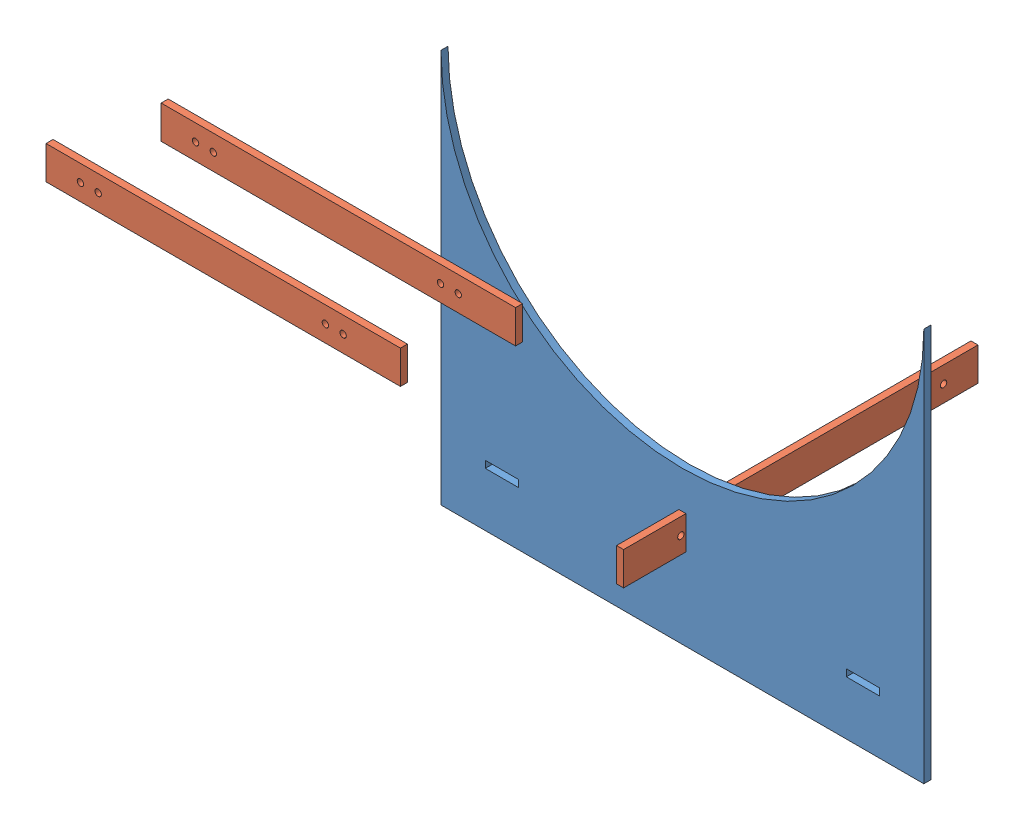
SolidWorks assembly Assem2, configuration Default. Lengths in mm.
Overall size (361.3 177.8 166.84).
4 component instances, 2 part files, 2 mates.
Components (placement in the parent):
- jug stand 1-1: jug stand 1 [Default] at (-17.5585 11.2843 0.0115) size (218 177.8 3.17)
- Newstabalizer-1: Newstabalizer [Default] at (-15.971 -33.1657 -48.6664) x (0 0 1) z (-1 0 0) size (160 15 3.17)
- Newstabalizer-2: Newstabalizer [Default] at (-189.8616 2.0743 35.0032) size (160 15 3.17)
- Newstabalizer-3: Newstabalizer [Default] at (-152.705 29.0628 20.1755) size (160 15 3.17)
Mates (geometry in assembly coordinates):
- Coincident1: coincident anti-aligned: plane of jug stand 1-1 through (-19.146 -25.6657 3.1865) normal (1 0 0); plane of Newstabalizer-1 through (-19.146 -33.1657 -48.6664) normal (-1 0 0)
- Coincident3: coincident anti-aligned: plane of jug stand 1-1 through (-15.971 -40.6657 3.1865) normal (0 1 0); plane of Newstabalizer-1 through (-19.146 -40.6657 -128.6664) normal (0 -1 0)
